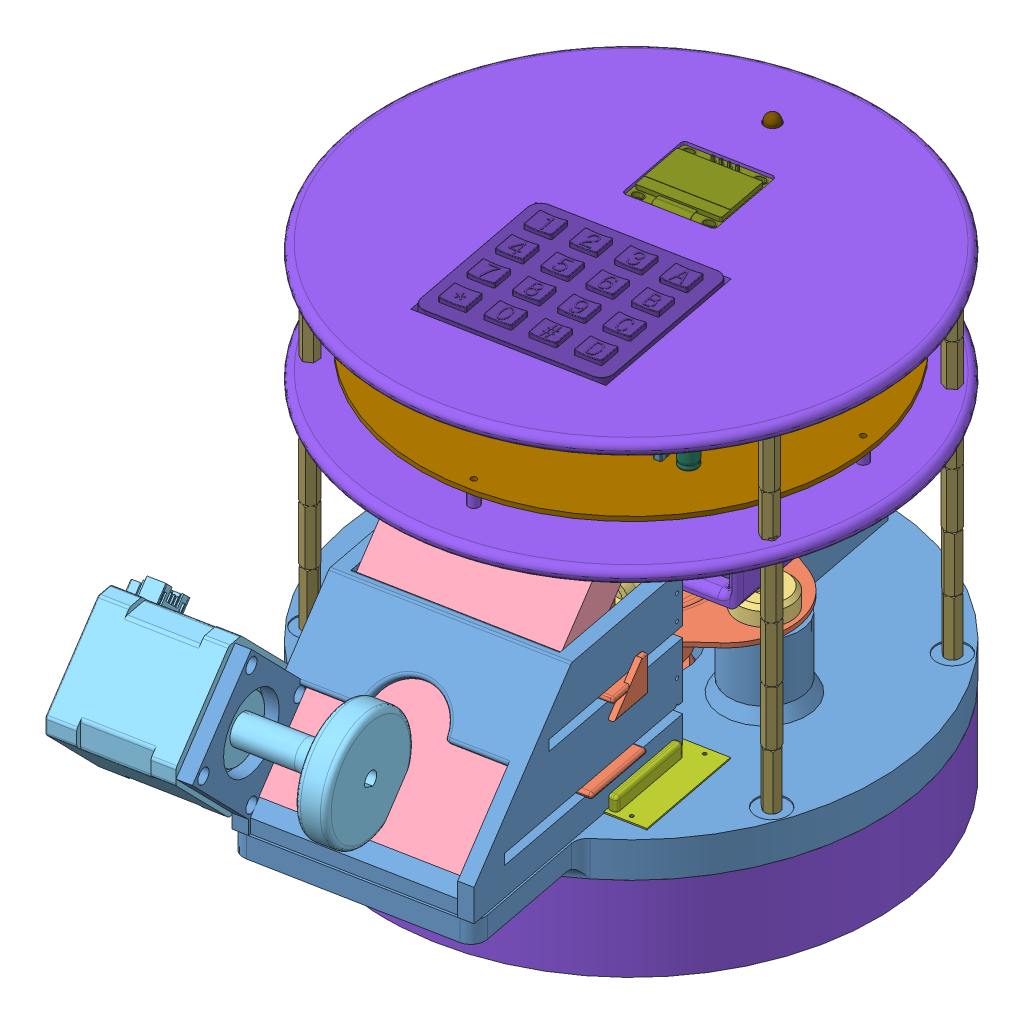
SolidWorks assembly Overall Assemble, configuration Default. Lengths in mm.
Overall size (252.3 171.03 293.45).
73 component instances, 30 part files, 83 mates.
Components (placement in the parent):
- Bottom-1: Bottom [Default] at (-33.8005 25.3575 11.2218) x (0.982057 0 -0.188586) z (0.188586 0 0.982057) size (177.8 76.06 215.9)
  - Bottom-1: Bottom [Default] at (8.1553 61.8283 175.2845) size (177.8 38.54 215.9)
  - Mounted Bearings-1: Mounted Bearings [7208K54] at (8.1553 101.5158 175.2845) x (1 0 0) z (0 1 0) size (104.77 57.15 28.57)
  - Long Bolt-1: Long Bolt [92220A261] at (-33.1197 88.8158 175.2845) x (0 -1 0) z (0.959154 0 0.282883) size (32.81 19.05 19.05)
  - Long Bolt-2: Long Bolt [92220A261] at (49.4303 88.8158 175.2845) x (0 -1 0) z (-0.057678 0 -0.998335) size (32.81 19.05 19.05)
  - Main Shaft-1: Main Shaft [Default] at (8.1553 38.9683 175.2845) x (0.351619 0 0.936143) z (-0.936143 0 0.351619) size (19.05 60.96 19.05)
  - Stepper Motor-1: Stepper Motor [Default] at (8.1553 115.0283 119.1505) x (-1 0 0) z (0 0 1) size (42 64 48.25)
  - Magnet-1: Magnet [Default] at (21.4903 70.7183 223.5445) size (25.4 3.17 25.4)
  - Magnet-2: Magnet [Default] at (-5.1797 70.7183 223.5445) size (25.4 3.17 25.4)
  - Magnet Cap Top-1: Magnet Cap Top [Default] at (8.1553 75.0283 223.9255) x (-1 0 0) z (0 0 1) size (101.6 0.5 38.1)
- Middle-1: Middle [Default] at (-6.6233 265.0701 334.6271) x (0.982057 0 -0.188586) z (-0.188586 0 -0.982057) size (215.53 58.96 215.53)
  - Middle-1: Middle [Default] at (42.4554 80.6123 147.4431) size (177.8 41.91 177.8)
  - PCB-2: PCB [Default] at (42.4554 72.6623 147.4431) x (0.707107 0 -0.707107) z (0.707107 0 0.707107) size (152.4 1.6 152.4)
  - Battery-1: Battery [Default] at (42.4554 112.3623 153.7931) x (1 0 0) z (0 -1 0) size (105.41 63.5 24.64)
  - Arduino Nano-1: Arduino Nano [Default] at (40.7952 58.8985 147.763) x (-1 0 0) z (0 0 1) size (44.95 20.74 17.81)
  - XL4015 DC-DC 5A (CC-CV)-1: XL4015 DC-DC 5A (CC-CV) [Default] at (16.9554 72.6623 177.3231) x (1 0 0) z (0 -1 0) size (51 26 18.15)
  - Mini BreadBoard-1: Mini BreadBoard [Default] at (-2.5946 67.4623 163.7119) x (0 0 -1) z (-1 0 0) size (48 9.4 35.7)
  - A4988-1: A4988 [Default] at (-15.9646 70.3723 179.8319) x (0 0 -1) z (0 -1 0) size (20.32 15.24 16.04)
  - A4988-2: A4988 [Default] at (11.9754 70.3723 179.8319) x (0 0 -1) z (0 -1 0) size (20.32 15.24 16.04)
  - A4988-3: A4988 [Default] at (-43.9046 70.3723 179.8319) x (0 0 -1) z (0 -1 0) size (20.32 15.24 16.04)
  - Capacitor (S)-1: Capacitor (S) [Default] at (28.4854 72.9623 125.8819) x (0.986985 0 0.160814) z (0 -1 0) size (6.32 6.3 14.2)
  - Capacitor (S)-2: Capacitor (S) [Default] at (28.4854 72.6623 111.8619) x (-0.984027 0 0.178021) z (0 -1 0) size (6.32 6.3 14.2)
  - Capacitor (S)-3: Capacitor (S) [Default] at (56.4254 72.9623 111.8619) x (-0.893651 0 0.448762) z (0 -1 0) size (6.32 6.3 14.2)
  - Capacitor (S)-4: Capacitor (S) [Default] at (56.4254 72.9623 125.8819) x (-0.978073 0 0.208264) z (0 -1 0) size (6.32 6.3 14.2)
  - Capacitor (S)-5: Capacitor (S) [Default] at (84.3654 72.9623 125.8819) x (0 0 1) z (0 -1 0) size (6.32 6.3 14.2)
  - Capacitor (S)-6: Capacitor (S) [Default] at (84.3654 72.9623 111.8619) x (-0.96585 0 0.259103) z (0 -1 0) size (6.32 6.3 14.2)
- Top-1: Top [Default] at (-85.585 129.1279 71.1518) x (0.982057 0 -0.188586) z (0.188586 0 0.982057) size (177.8 15 177.8)
  - Middle-1: Middle [1] at (70.3126 90.2499 126.1956) size (177.8 5.08 177.8)
  - OLED Screen-1: OLED Screen [Default] at (70.3126 94.3899 95.5906) x (1 0 0) z (0 1 0) size (28.3 27.65 10.4)
  - Keypad-1: Keypad [Výchozí] at (70.3126 89.2899 153.6906) x (1 0 0) z (0 1 0) size (65 69 8.87)
  - RBG Module-1: RBG Module [Default] at (70.3126 83.4999 61.6156) x (-0.000001 0 1) z (-1 0 -0.000001) size (15 15 24.23)
- Card Shooter-1: Card Shooter [Default] at (125.3645 69.5191 229.4183) x (0.188586 0 0.982057) z (-0.982057 0 0.188586) size (123.63 84.8 118.6)
  - Shooting Frame-1: Shooting Frame [Default] at (-3.3965 69.3135 69.54) size (120.88 57.65 74.93)
  - Stepper Motor-1: Stepper Motor [Default] at (56.6717 61.73 184.97) x (0.707107 0.707107 0) z (-0.707107 0.707107 0) size (42 64 48.25)
  - Triangle Push-1: Triangle Push [Default] at (-16.5248 65.5458 75.89) size (51.9 46.82 81.28)
  - Shooter Back-1: Shooter Back [Default] at (-35.9932 62.1168 107.005) x (0 -1 0) z (0 0 1) size (43.18 7.62 64.77)
  - Card Deck-1: Card Deck [Default] at (11.9696 82.734 107.005) x (0.707107 -0.707107 0) z (0 0 -1) size (104.14 15.24 63.5)
  - Shooting Wheel-1: Shooting Wheel [Default] at (56.6717 61.73 112.62) x (-0.906141 -0.422976 0) z (0.422976 -0.906141 0) size (40 40.16 40)
  - Spring-1: Spring [9657K347] at (4.6468 76.8535 107.0399) x (0 0 -1) z (1 0 0) size (8.27 8.27 38.43)
  - Magnet-1: Magnet [Default] at (-17.8957 30.8668 94.305) size (25.4 3.17 25.4)
  - Magnet-2: Magnet [Default] at (-17.8957 30.8668 119.705) size (25.4 3.17 25.4)
  - Magnet Cap-1: Magnet Cap [Bottom Cap] at (-17.8957 32.5432 69.54) x (-1 0 0) z (0 1 0) size (30.48 13.33 6.35)
- Gear Base-1: Gear Base [Default] at (7.2646 56.7059 181.8231) size (177.8 30.48 177.8)
- Driven Gear-1: Driven Gear [Default] at (-3.3215 87.1859 126.6963) x (-0.830148 0 0.557543) z (0.557543 0 0.830148) size (39.41 25.4 39.34)
- Mounted Bearings-1: Mounted Bearings [7208K54] at (7.2646 64.3259 181.8231) x (-1 0 0) z (0 -1 0) size (104.77 57.15 28.57)
- Bottom Bolt-1: Bottom Bolt [91253A489] at (48.5396 65.4155 181.8231) x (1 0 0) z (0 1 0) size (23.83 23.83 16.93)
- Bottom Nut-1: Bottom Nut [96557A130] at (48.5396 59.8967 181.8231) x (0.431881 0 -0.90193) z (0.90193 0 0.431881) size (17.86 7.06 20.62)
- Bottom Bolt-2: Bottom Bolt [91253A489] at (-33.2613 65.7473 181.287) x (-0.563339 0.003391 -0.826219) z (0.034909 0.999196 -0.0197) size (23.83 23.83 16.93)
- Bottom Nut-2: Bottom Nut [96557A130] at (-34.0104 59.8967 181.8231) x (0.808539 0 -0.588442) z (0.588442 0 0.808539) size (17.86 7.06 20.62)
- M3_M_TO_F_20MM_STANDOFF.step-17: M3_M_TO_F_20MM_STANDOFF.step [Default] at (-55.1591 129.3779 235.8395) x (0.980137 0 0.198323) z (0 -1 0) size (5.78 5.78 26)
- M3_M_TO_F_20MM_STANDOFF.step-18: M3_M_TO_F_20MM_STANDOFF.step [Default] at (85.2561 169.3779 208.8754) x (-0.925159 0 -0.379579) z (0 -1 0) size (5.78 5.78 26)
- M3_M_TO_F_20MM_STANDOFF.step-19: M3_M_TO_F_20MM_STANDOFF.step [Default] at (85.2561 149.3779 208.8754) x (-0.956689 0 -0.291113) z (0 -1 0) size (5.78 5.78 26)
- M3_M_TO_F_20MM_STANDOFF.step-20: M3_M_TO_F_20MM_STANDOFF.step [Default] at (85.2561 129.3779 208.8754) x (-0.963161 0 -0.268925) z (0 -1 0) size (5.78 5.78 26)
- M3_M_TO_F_20MM_STANDOFF.step-21: M3_M_TO_F_20MM_STANDOFF.step [Default] at (85.2561 109.3779 208.8754) x (0.123107 0 -0.992393) z (0 -1 0) size (5.78 5.78 26)
- M3_M_TO_F_20MM_STANDOFF.step-2: M3_M_TO_F_20MM_STANDOFF.step [Default] at (-70.7269 109.3779 154.7708) x (0.123107 0 -0.992393) z (0 -1 0) size (5.78 5.78 26)
- M3_M_TO_F_20MM_STANDOFF.step-3: M3_M_TO_F_20MM_STANDOFF.step [Default] at (-70.7269 149.3779 154.7708) x (-0.956689 0 -0.291113) z (0 -1 0) size (5.78 5.78 26)
- M3_M_TO_F_20MM_STANDOFF.step-6: M3_M_TO_F_20MM_STANDOFF.step [Default] at (-70.7269 169.3779 154.7708) x (-0.989707 0 -0.14311) z (0 -1 0) size (5.78 5.78 26)
- M3_M_TO_F_20MM_STANDOFF.step-7: M3_M_TO_F_20MM_STANDOFF.step [Default] at (-70.7269 129.3779 154.7708) x (-0.287457 0 -0.957794) z (0 -1 0) size (5.78 5.78 26)
- M3_M_TO_F_20MM_STANDOFF.step-10: M3_M_TO_F_20MM_STANDOFF.step [Default] at (69.6884 149.3779 127.8066) x (-0.956689 0 -0.291113) z (0 -1 0) size (5.78 5.78 26)
- M3_M_TO_F_20MM_STANDOFF.step-11: M3_M_TO_F_20MM_STANDOFF.step [Default] at (69.6884 169.3779 127.8066) x (0.108358 0 0.994112) z (0 -1 0) size (5.78 5.78 26)
- M3_M_TO_F_20MM_STANDOFF.step-12: M3_M_TO_F_20MM_STANDOFF.step [Default] at (69.6884 129.3779 127.8066) x (0.834897 0 0.550406) z (0 -1 0) size (5.78 5.78 26)
- M3_M_TO_F_20MM_STANDOFF.step-13: M3_M_TO_F_20MM_STANDOFF.step [Default] at (69.6884 109.3779 127.8066) x (0.123107 0 -0.992393) z (0 -1 0) size (5.78 5.78 26)
- M3_M_TO_F_20MM_STANDOFF.step-14: M3_M_TO_F_20MM_STANDOFF.step [Default] at (-55.1591 109.3779 235.8395) x (-0.488206 0 0.872728) z (0 -1 0) size (5.78 5.78 26)
- M3_M_TO_F_20MM_STANDOFF.step-15: M3_M_TO_F_20MM_STANDOFF.step [Default] at (-55.1591 169.3779 235.8395) x (-0.640969 0 -0.767567) z (0 -1 0) size (5.78 5.78 26)
- M3_M_TO_F_20MM_STANDOFF.step-16: M3_M_TO_F_20MM_STANDOFF.step [Default] at (-55.1591 149.3779 235.8395) x (-0.383557 0 -0.923517) z (0 -1 0) size (5.78 5.78 26)
- M3_M_TO_F_20MM_STANDOFF.step-22: M3_M_TO_F_20MM_STANDOFF.step [Default] at (-70.7269 189.3779 154.7708) x (-0.047329 0 -0.998879) z (0 -1 0) size (5.78 5.78 26)
- M3_M_TO_F_20MM_STANDOFF.step-24: M3_M_TO_F_20MM_STANDOFF.step [Default] at (-70.7269 209.3779 154.7708) x (0.757899 0 -0.652372) z (0 1 0) size (5.78 5.78 26)
- M3_M_TO_F_20MM_STANDOFF.step-27: M3_M_TO_F_20MM_STANDOFF.step [Default] at (-55.1591 189.3779 235.8395) x (-0.047329 0 -0.998879) z (0 -1 0) size (5.78 5.78 26)
- M3_M_TO_F_20MM_STANDOFF.step-28: M3_M_TO_F_20MM_STANDOFF.step [Default] at (-55.1591 209.3779 235.8395) x (0.768824 0 -0.63946) z (0 1 0) size (5.78 5.78 26)
- M3_M_TO_F_20MM_STANDOFF.step-29: M3_M_TO_F_20MM_STANDOFF.step [Default] at (69.6884 189.3779 127.8066) x (-0.2229 0 -0.974841) z (0 -1 0) size (5.78 5.78 26)
- M3_M_TO_F_20MM_STANDOFF.step-30: M3_M_TO_F_20MM_STANDOFF.step [Default] at (69.6884 209.3779 127.8066) x (0.757899 0 -0.652372) z (0 1 0) size (5.78 5.78 26)
- M3_M_TO_F_20MM_STANDOFF.step-31: M3_M_TO_F_20MM_STANDOFF.step [Default] at (83.9147 189.3779 208.325) x (-0.044753 0 -0.998998) z (0 -1 0) size (5.78 5.78 26)
- M3_M_TO_F_20MM_STANDOFF.step-32: M3_M_TO_F_20MM_STANDOFF.step [Default] at (83.9147 209.3779 208.325) x (0.757899 0 -0.652372) z (0 1 0) size (5.78 5.78 26)
Mates (geometry in assembly coordinates):
- Coincident1: coincident anti-aligned: plane of Gear Base-1 through (7.2646 74.4859 181.8231) normal (0 1 0); plane of Driven Gear-1 through (-3.3215 74.4859 126.6963) normal (0 -1 0)
- Concentric1: concentric aligned: cylinder of Gear Base-1 through (7.2646 87.1859 181.8231) axis (0 -1 0) radius 88.9; cylinder of Bottom-1/Bottom-1 through (7.2646 99.8859 181.8231) axis (0 -1 0) radius 88.9
- Coincident2: coincident anti-aligned: plane of Gear Base-1 through (50.4446 64.3259 172.6454) normal (0 1 0); plane of Mounted Bearings-1 through (36.4024 64.3259 181.8231) normal (0 -1 0)
- Concentric2: concentric aligned: cylinder of Bottom-1/Main Shaft-1 through (7.2646 125.2859 181.8231) axis (0 -1 0) radius 9.525; cylinder of Mounted Bearings-1 through (7.2646 64.3259 181.8231) axis (0 -1 0) radius 16.4211
- Concentric3: concentric anti-aligned: cylinder of Gear Base-1 through (-34.0104 38.7454 181.8231) axis (0 1 0) radius 6.35; cylinder of Mounted Bearings-1 through (-34.0104 65.9134 181.8231) axis (0 -1 0) radius 5.5563
- Coincident3: coincident anti-aligned: plane of Gear Base-1 through (50.4446 64.3259 172.6454) normal (0 1 0); plane of Bottom-1/Main Shaft-1 through (7.2646 64.3259 181.8231) normal (0 -1 0)
- Concentric4: concentric anti-aligned: cylinder of Driven Gear-1 through (-3.3215 99.8859 126.6963) axis (0 -1 0) radius 10.16; cylinder of Bottom-1/Bottom-1 through (-3.3215 51.2648 126.6963) axis (0 1 0) radius 12.7
- Concentric5: concentric aligned: cylinder of Mounted Bearings-1 through (48.5396 65.9134 181.8231) axis (0 -1 0) radius 5.5563; cone of Bottom Bolt-1 through (48.5396 66.6262 181.8231) axis (0 -1 0)
- Coincident4: coincident aligned: circle of Mounted Bearings-1; cone of Bottom Bolt-1 through (48.5396 66.9776 181.8231) axis (0 -1 0)
- Concentric6: concentric aligned: cylinder of Gear Base-1 through (48.5396 63.0559 181.8231) axis (0 -1 0) radius 12.7; cylinder of Bottom Nut-1 through (48.5396 63.0559 181.8231) axis (0 -1 0) radius 8.3306
- Coincident5: coincident anti-aligned: plane of Gear Base-1 through (48.5396 63.0559 181.8231) normal (0 -1 0); plane of Bottom Nut-1 through (48.5396 63.0559 181.8231) normal (0 1 0)
- Tangent1: tangent: circle of Mounted Bearings-1; face of Bottom Bolt-2
- Concentric8: concentric aligned: cylinder of Gear Base-1 through (-34.0104 63.0559 181.8231) axis (0 -1 0) radius 12.7; cylinder of Bottom Nut-2 through (-34.0104 63.0559 181.8231) axis (0 -1 0) radius 8.3306
- Coincident7: coincident anti-aligned: plane of Gear Base-1 through (-34.0104 63.0559 181.8231) normal (0 -1 0); plane of Bottom Nut-2 through (-34.0104 63.0559 181.8231) normal (0 1 0)
- Concentric13: concentric aligned: cylinder of Bottom-1/Bottom-1 through (-70.7269 99.3779 154.7708) axis (0 1 0) radius 5.715; cylinder of M3_M_TO_F_20MM_STANDOFF.step-2 through (-70.7269 117.3779 154.7708) axis (0 1 0) radius 1.45
- Coincident12: coincident anti-aligned: plane of Bottom-1/Bottom-1 through (-70.7269 99.3779 154.7708) normal (0 1 0); plane of M3_M_TO_F_20MM_STANDOFF.step-2 through (-70.7269 99.3779 154.7708) normal (0 -1 0)
- Concentric14: concentric anti-aligned: cylinder of M3_M_TO_F_20MM_STANDOFF.step-2 through (-70.7269 117.3779 154.7708) axis (0 1 0) radius 1.45; cylinder of M3_M_TO_F_20MM_STANDOFF.step-7 through (-70.7269 119.3779 154.7708) axis (0 -1 0) radius 1.25
- Concentric15: concentric anti-aligned: cylinder of M3_M_TO_F_20MM_STANDOFF.step-3 through (-70.7269 139.3779 154.7708) axis (0 -1 0) radius 1.25; cylinder of M3_M_TO_F_20MM_STANDOFF.step-7 through (-70.7269 137.3779 154.7708) axis (0 1 0) radius 1.45
- Concentric16: concentric anti-aligned: cylinder of M3_M_TO_F_20MM_STANDOFF.step-3 through (-70.7269 157.3779 154.7708) axis (0 1 0) radius 1.45; cylinder of M3_M_TO_F_20MM_STANDOFF.step-6 through (-70.7269 159.3779 154.7708) axis (0 -1 0) radius 1.25
- Concentric19: concentric anti-aligned: cylinder of M3_M_TO_F_20MM_STANDOFF.step-10 through (69.6884 139.3779 127.8066) axis (0 -1 0) radius 1.25; cylinder of M3_M_TO_F_20MM_STANDOFF.step-11 through (69.6884 177.3779 127.8066) axis (0 1 0) radius 1.45
- Concentric20: concentric anti-aligned: cylinder of M3_M_TO_F_20MM_STANDOFF.step-11 through (69.6884 159.3779 127.8066) axis (0 -1 0) radius 1.25; cylinder of M3_M_TO_F_20MM_STANDOFF.step-12 through (69.6884 137.3779 127.8066) axis (0 1 0) radius 1.45
- Concentric21: concentric anti-aligned: cylinder of M3_M_TO_F_20MM_STANDOFF.step-12 through (69.6884 119.3779 127.8066) axis (0 -1 0) radius 1.25; cylinder of M3_M_TO_F_20MM_STANDOFF.step-13 through (69.6884 117.3779 127.8066) axis (0 1 0) radius 1.45
- Coincident14: coincident anti-aligned: plane of Bottom-1/Bottom-1 through (69.6884 99.3779 127.8066) normal (0 1 0); plane of M3_M_TO_F_20MM_STANDOFF.step-13 through (69.6884 99.3779 127.8066) normal (0 -1 0)
- Concentric22: concentric aligned: circle of Bottom-1/Bottom-1; cylinder of M3_M_TO_F_20MM_STANDOFF.step-13 through (69.6884 117.3779 127.8066) axis (0 1 0) radius 1.45
- Concentric23: concentric anti-aligned: cylinder of M3_M_TO_F_20MM_STANDOFF.step-14 through (-55.1591 99.3779 235.8395) axis (0 -1 0) radius 1.25; cylinder of M3_M_TO_F_20MM_STANDOFF.step-15 through (-55.1591 177.3779 235.8395) axis (0 1 0) radius 1.45
- Concentric24: concentric anti-aligned: cylinder of M3_M_TO_F_20MM_STANDOFF.step-15 through (-55.1591 159.3779 235.8395) axis (0 -1 0) radius 1.25; cylinder of M3_M_TO_F_20MM_STANDOFF.step-16 through (-55.1591 157.3779 235.8395) axis (0 1 0) radius 1.45
- Concentric25: concentric anti-aligned: cylinder of M3_M_TO_F_20MM_STANDOFF.step-16 through (-55.1591 139.3779 235.8395) axis (0 -1 0) radius 1.25; cylinder of M3_M_TO_F_20MM_STANDOFF.step-17 through (-55.1591 137.3779 235.8395) axis (0 1 0) radius 1.45
- Concentric26: concentric aligned: cylinder of Bottom-1/Bottom-1 through (-55.1591 99.3779 235.8395) axis (0 1 0) radius 5.715; cylinder of M3_M_TO_F_20MM_STANDOFF.step-14 through (-55.1591 117.3779 235.8395) axis (0 1 0) radius 1.45
- Coincident15: coincident anti-aligned: plane of Bottom-1/Bottom-1 through (-55.1591 99.3779 235.8395) normal (0 1 0); plane of M3_M_TO_F_20MM_STANDOFF.step-14 through (-55.1591 99.3779 235.8395) normal (0 -1 0)
- Concentric27: concentric anti-aligned: cylinder of M3_M_TO_F_20MM_STANDOFF.step-18 through (85.2561 159.3779 208.8754) axis (0 -1 0) radius 1.25; cylinder of M3_M_TO_F_20MM_STANDOFF.step-19 through (85.2561 157.3779 208.8754) axis (0 1 0) radius 1.45
- Concentric28: concentric anti-aligned: cylinder of M3_M_TO_F_20MM_STANDOFF.step-19 through (85.2561 139.3779 208.8754) axis (0 -1 0) radius 1.25; cylinder of M3_M_TO_F_20MM_STANDOFF.step-20 through (85.2561 137.3779 208.8754) axis (0 1 0) radius 1.45
- Concentric29: concentric anti-aligned: cylinder of M3_M_TO_F_20MM_STANDOFF.step-20 through (85.2561 119.3779 208.8754) axis (0 -1 0) radius 1.25; cylinder of M3_M_TO_F_20MM_STANDOFF.step-21 through (85.2561 117.3779 208.8754) axis (0 1 0) radius 1.45
- Coincident16: coincident anti-aligned: plane of Bottom-1/Bottom-1 through (85.2561 99.3779 208.8754) normal (0 1 0); plane of M3_M_TO_F_20MM_STANDOFF.step-21 through (85.2561 99.3779 208.8754) normal (0 -1 0)
- Concentric30: concentric aligned: circle of Bottom-1/Bottom-1; cylinder of M3_M_TO_F_20MM_STANDOFF.step-21 through (85.2561 117.3779 208.8754) axis (0 1 0) radius 1.45
- Coincident17: coincident anti-aligned: plane of M3_M_TO_F_20MM_STANDOFF.step-2 through (-70.7269 119.3779 154.7708) normal (0 1 0); plane of M3_M_TO_F_20MM_STANDOFF.step-7 through (-70.7269 119.3779 154.7708) normal (0 -1 0)
- Coincident18: coincident anti-aligned: plane of M3_M_TO_F_20MM_STANDOFF.step-3 through (-70.7269 139.3779 154.7708) normal (0 -1 0); plane of M3_M_TO_F_20MM_STANDOFF.step-7 through (-70.7269 139.3779 154.7708) normal (0 1 0)
- Coincident19: coincident anti-aligned: plane of M3_M_TO_F_20MM_STANDOFF.step-3 through (-70.7269 159.3779 154.7708) normal (0 1 0); plane of M3_M_TO_F_20MM_STANDOFF.step-6 through (-70.7269 159.3779 154.7708) normal (0 -1 0)
- Coincident20: coincident anti-aligned: plane of M3_M_TO_F_20MM_STANDOFF.step-12 through (69.6884 119.3779 127.8066) normal (0 -1 0); plane of M3_M_TO_F_20MM_STANDOFF.step-13 through (69.6884 119.3779 127.8066) normal (0 1 0)
- Coincident21: coincident anti-aligned: plane of M3_M_TO_F_20MM_STANDOFF.step-10 through (69.6884 139.3779 127.8066) normal (0 -1 0); plane of M3_M_TO_F_20MM_STANDOFF.step-12 through (69.6884 139.3779 127.8066) normal (0 1 0)
- Coincident22: coincident anti-aligned: plane of M3_M_TO_F_20MM_STANDOFF.step-10 through (69.6884 159.3779 127.8066) normal (0 1 0); plane of M3_M_TO_F_20MM_STANDOFF.step-11 through (69.6884 159.3779 127.8066) normal (0 -1 0)
- Coincident23: coincident aligned: circle of M3_M_TO_F_20MM_STANDOFF.step-20; plane of M3_M_TO_F_20MM_STANDOFF.step-21 through (85.2561 119.3779 208.8754) normal (0 1 0)
- Coincident24: coincident anti-aligned: plane of M3_M_TO_F_20MM_STANDOFF.step-19 through (85.2561 139.3779 208.8754) normal (0 -1 0); plane of M3_M_TO_F_20MM_STANDOFF.step-20 through (85.2561 139.3779 208.8754) normal (0 1 0)
- Coincident25: coincident anti-aligned: plane of M3_M_TO_F_20MM_STANDOFF.step-18 through (85.2561 159.3779 208.8754) normal (0 -1 0); plane of M3_M_TO_F_20MM_STANDOFF.step-19 through (85.2561 159.3779 208.8754) normal (0 1 0)
- Coincident26: coincident anti-aligned: plane of M3_M_TO_F_20MM_STANDOFF.step-14 through (-55.1591 119.3779 235.8395) normal (0 1 0); plane of M3_M_TO_F_20MM_STANDOFF.step-17 through (-55.1591 119.3779 235.8395) normal (0 -1 0)
- Coincident27: coincident anti-aligned: plane of M3_M_TO_F_20MM_STANDOFF.step-16 through (-55.1591 139.3779 235.8395) normal (0 -1 0); plane of M3_M_TO_F_20MM_STANDOFF.step-17 through (-55.1591 139.3779 235.8395) normal (0 1 0)
- Coincident28: coincident anti-aligned: plane of M3_M_TO_F_20MM_STANDOFF.step-15 through (-55.1591 159.3779 235.8395) normal (0 -1 0); plane of M3_M_TO_F_20MM_STANDOFF.step-16 through (-55.1591 159.3779 235.8395) normal (0 1 0)
- Concentric31: concentric anti-aligned: cylinder of Bottom-1/Bottom-1 through (7.2646 99.8859 181.8231) axis (0 -1 0) radius 88.9; cylinder of Middle-1/PCB-2 through (7.2646 190.8079 181.8231) axis (0 1 0) radius 76.2
- Coincident29: coincident anti-aligned: plane of M3_M_TO_F_20MM_STANDOFF.step-15 through (-55.1591 179.3779 235.8395) normal (0 1 0); plane of Middle-1/Middle-1 through (7.2646 179.3779 181.8231) normal (0 -1 0)
- Parallel2: parallel anti-aligned: plane of Bottom-1/Stepper Motor-1 through (-24.0504 140.3859 109.2932) normal (-0.188586 0 -0.982057); plane of Middle-1/Battery-1 through (-37.2102 177.3459 216.2277) normal (0.188586 0 0.982057)
- Concentric32: concentric aligned: cylinder of M3_M_TO_F_20MM_STANDOFF.step-6 through (-70.7269 177.3779 154.7708) axis (0 1 0) radius 1.45; cylinder of M3_M_TO_F_20MM_STANDOFF.step-22 through (-70.7269 197.3779 154.7708) axis (0 1 0) radius 1.45
- Coincident31: coincident aligned: plane of Middle-1/Middle-1 through (7.2646 179.3779 181.8231) normal (0 -1 0); plane of M3_M_TO_F_20MM_STANDOFF.step-22 through (-70.7269 179.3779 154.7708) normal (0 -1 0)
- Concentric33: concentric aligned: cylinder of M3_M_TO_F_20MM_STANDOFF.step-22 through (-70.7269 197.3779 154.7708) axis (0 1 0) radius 1.45; cylinder of M3_M_TO_F_20MM_STANDOFF.step-24 through (-70.7269 219.3779 154.7708) axis (0 1 0) radius 1.25
- Coincident32: coincident anti-aligned: plane of M3_M_TO_F_20MM_STANDOFF.step-22 through (-70.7269 199.3779 154.7708) normal (0 1 0); plane of M3_M_TO_F_20MM_STANDOFF.step-24 through (-70.7269 199.3779 154.7708) normal (0 -1 0)
- Coincident33: coincident anti-aligned: plane of M3_M_TO_F_20MM_STANDOFF.step-27 through (-55.1591 199.3779 235.8395) normal (0 1 0); plane of M3_M_TO_F_20MM_STANDOFF.step-28 through (-55.1591 199.3779 235.8395) normal (0 -1 0)
- Concentric34: concentric aligned: cylinder of M3_M_TO_F_20MM_STANDOFF.step-27 through (-55.1591 197.3779 235.8395) axis (0 1 0) radius 1.45; cylinder of M3_M_TO_F_20MM_STANDOFF.step-28 through (-55.1591 219.3779 235.8395) axis (0 1 0) radius 1.25
- Coincident34: coincident anti-aligned: plane of M3_M_TO_F_20MM_STANDOFF.step-29 through (69.6884 199.3779 127.8066) normal (0 1 0); plane of M3_M_TO_F_20MM_STANDOFF.step-30 through (69.6884 199.3779 127.8066) normal (0 -1 0)
- Concentric35: concentric aligned: cylinder of M3_M_TO_F_20MM_STANDOFF.step-29 through (69.6884 197.3779 127.8066) axis (0 1 0) radius 1.45; cylinder of M3_M_TO_F_20MM_STANDOFF.step-30 through (69.6884 219.3779 127.8066) axis (0 1 0) radius 1.25
- Coincident35: coincident anti-aligned: plane of M3_M_TO_F_20MM_STANDOFF.step-31 through (83.9147 199.3779 208.325) normal (0 1 0); plane of M3_M_TO_F_20MM_STANDOFF.step-32 through (83.9147 199.3779 208.325) normal (0 -1 0)
- Concentric36: concentric aligned: cylinder of M3_M_TO_F_20MM_STANDOFF.step-31 through (83.9147 197.3779 208.325) axis (0 1 0) radius 1.45; cylinder of M3_M_TO_F_20MM_STANDOFF.step-32 through (83.9147 219.3779 208.325) axis (0 1 0) radius 1.25
- Concentric37: concentric anti-aligned: cylinder of M3_M_TO_F_20MM_STANDOFF.step-15 through (-55.1591 177.3779 235.8395) axis (0 1 0) radius 1.45; cylinder of M3_M_TO_F_20MM_STANDOFF.step-27 through (-55.1591 179.3779 235.8395) axis (0 -1 0) radius 1.25
- Coincident36: coincident aligned: plane of Middle-1/Middle-1 through (7.2646 179.3779 181.8231) normal (0 -1 0); plane of M3_M_TO_F_20MM_STANDOFF.step-27 through (-55.1591 179.3779 235.8395) normal (0 -1 0)
- Concentric38: concentric anti-aligned: line of M3_M_TO_F_20MM_STANDOFF.step-18 through (83.9147 179.6279 208.325) axis (0 1 0); cylinder of M3_M_TO_F_20MM_STANDOFF.step-31 through (83.9147 179.3779 208.325) axis (0 -1 0) radius 1.25
- Coincident38: coincident aligned: plane of Middle-1/Middle-1 through (7.2646 179.3779 181.8231) normal (0 -1 0); plane of M3_M_TO_F_20MM_STANDOFF.step-31 through (83.9147 179.3779 208.325) normal (0 -1 0)
- Concentric39: concentric anti-aligned: cylinder of M3_M_TO_F_20MM_STANDOFF.step-11 through (69.6884 177.3779 127.8066) axis (0 1 0) radius 1.45; cylinder of M3_M_TO_F_20MM_STANDOFF.step-29 through (69.6884 179.3779 127.8066) axis (0 -1 0) radius 1.25
- Coincident39: coincident aligned: plane of Middle-1/Middle-1 through (7.2646 179.3779 181.8231) normal (0 -1 0); plane of M3_M_TO_F_20MM_STANDOFF.step-29 through (69.6884 179.3779 127.8066) normal (0 -1 0)
- Concentric40: concentric anti-aligned: circle of Middle-1/PCB-2; circle of Top-1/Middle-1
- Parallel3: parallel aligned: plane of Middle-1/Middle-1 through (-0.8785 184.4579 139.4179) normal (-0.188586 0 -0.982057); plane of Top-1/Keypad-1 through (32.5783 225.6179 176.0405) normal (-0.188586 0 -0.982057)
- Coincident41: coincident anti-aligned: plane of M3_M_TO_F_20MM_STANDOFF.step-28 through (-55.1591 219.3779 235.8395) normal (0 1 0); plane of Top-1/Middle-1 through (7.2646 219.3779 181.8231) normal (0 -1 0)
- Concentric41: concentric aligned: cylinder of Gear Base-1 through (7.2646 87.1859 181.8231) axis (0 -1 0) radius 88.9; cylinder of Middle-1/Bottom-1/Bottom-1 through (7.2646 102.4259 181.8231) axis (0 -1 0) radius 88.9
- Concentric42: concentric aligned: cylinder of Middle-1/Bottom-1/Main Shaft-1 through (7.2646 127.8259 181.8231) axis (0 -1 0) radius 9.525; cylinder of Mounted Bearings-1 through (7.2646 64.3259 181.8231) axis (0 -1 0) radius 16.4211
- Coincident42: coincident anti-aligned: plane of Gear Base-1 through (50.4446 64.3259 172.6454) normal (0 1 0); plane of Middle-1/Bottom-1/Main Shaft-1 through (7.2646 64.3259 181.8231) normal (0 -1 0)
- Concentric43: concentric anti-aligned: cylinder of Driven Gear-1 through (-3.3215 99.8859 126.6963) axis (0 -1 0) radius 10.16; cylinder of Middle-1/Bottom-1/Bottom-1 through (61.0062 53.8048 198.0364) axis (0 1 0) radius 12.7
- Concentric44: concentric aligned: cylinder of Middle-1/Bottom-1/Bottom-1 through (67.4293 101.9179 125.3012) axis (0 1 0) radius 5.715; cylinder of M3_M_TO_F_20MM_STANDOFF.step-2 through (-70.7269 117.3779 154.7708) axis (0 1 0) radius 1.45
- Coincident43: coincident anti-aligned: plane of Middle-1/Bottom-1/Bottom-1 through (67.4293 101.9179 125.3012) normal (0 1 0); plane of M3_M_TO_F_20MM_STANDOFF.step-2 through (-70.7269 99.3779 154.7708) normal (0 -1 0)
- Coincident44: coincident anti-aligned: plane of Middle-1/Bottom-1/Bottom-1 through (26.1316 101.9179 262.1881) normal (0 1 0); plane of M3_M_TO_F_20MM_STANDOFF.step-13 through (69.6884 99.3779 127.8066) normal (0 -1 0)
- Concentric45: concentric aligned: circle of Middle-1/Bottom-1/Bottom-1; cylinder of M3_M_TO_F_20MM_STANDOFF.step-13 through (69.6884 117.3779 127.8066) axis (0 1 0) radius 1.45
- Concentric46: concentric aligned: cylinder of Middle-1/Bottom-1/Bottom-1 through (-11.6024 101.9179 101.458) axis (0 1 0) radius 5.715; cylinder of M3_M_TO_F_20MM_STANDOFF.step-14 through (-55.1591 117.3779 235.8395) axis (0 1 0) radius 1.45
- Coincident45: coincident anti-aligned: plane of Middle-1/Bottom-1/Bottom-1 through (-11.6024 101.9179 101.458) normal (0 1 0); plane of M3_M_TO_F_20MM_STANDOFF.step-14 through (-55.1591 99.3779 235.8395) normal (0 -1 0)
- Coincident46: coincident anti-aligned: plane of Middle-1/Bottom-1/Bottom-1 through (-52.9 101.9179 238.3449) normal (0 1 0); plane of M3_M_TO_F_20MM_STANDOFF.step-21 through (85.2561 99.3779 208.8754) normal (0 -1 0)
- Concentric47: concentric aligned: circle of Middle-1/Bottom-1/Bottom-1; cylinder of M3_M_TO_F_20MM_STANDOFF.step-21 through (85.2561 117.3779 208.8754) axis (0 1 0) radius 1.45
- Width1: width anti-aligned: plane of Card Shooter-1/Shooting Frame-1 through (56.4318 138.8325 239.197) normal (0.982057 0 -0.188586); plane of Bottom-1/Bottom-1 through (-17.1537 138.8325 253.3277) normal (-0.982057 0 0.188586); plane of Card Shooter-1/Shooting Frame-1 through (-32.3124 118.9359 107.046) normal (-0.982057 0 0.188586); plane of Bottom-1/Bottom-1 through (16.3289 118.9359 97.7053) normal (0.982057 0 -0.188586)
- Coincident47: coincident anti-aligned: plane of Bottom-1/Bottom-1 through (7.2646 99.8859 181.8231) normal (0 1 0); plane of Card Shooter-1/Shooting Frame-1 through (56.4318 99.8859 239.197) normal (0 -1 0)
- Coincident49: coincident anti-aligned: plane of Middle-1/Middle-1 through (13.2522 184.4579 213.0034) normal (0.188586 0 0.982057); plane of Card Shooter-1/Shooting Frame-1 through (-23.5405 104.9659 220.0687) normal (-0.188586 0 -0.982057)
